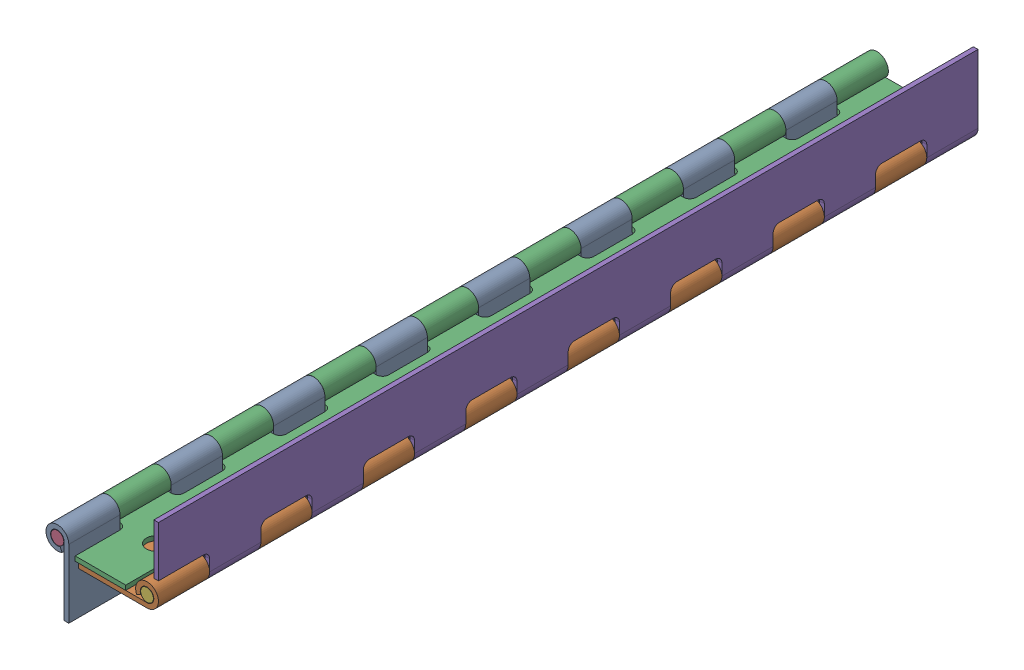
SolidWorks assembly FE-00004-07_, configuration Default. Lengths in mm.
Overall size (55.75 65.47 406.4).
6 component instances, 3 part files, 0 mates.
Components (placement in the parent):
- FE-00004-07A_-1: FE-00004-07A_ [Default] at origin size (11.3 39.53 406.4)
- FE-00004-07A_-2: FE-00004-07A_ [Default] at (15.9287 8.1335 0) x (0 -1 0) z (0 0 1) size (11.3 39.53 406.4)
- FE-00004-07B_-1: FE-00004-07B_ [Default] at (10.4195 10.4195 406.4) x (0 -1 0) z (0 0 -1) size (11.3 39.53 406.4)
- FE-00004-07C_-1: FE-00004-07C_ [Default] at (9.0309 31.5773 406.4) x (1 0 0) z (0 0 -1) size (6.35 6.35 406.4)
- FE-00004-07A_-3: FE-00004-07A_ [Default] at (44.45 36.6548 406.4) x (1 0 0) z (0 0 -1) size (11.3 39.53 406.4)
- FE-00004-07C_-2: FE-00004-07C_ [Default] at (52.4116 3.616 406.4) x (0.302716 -0.953081 0) z (0 0 -1) size (6.35 6.35 406.4)
